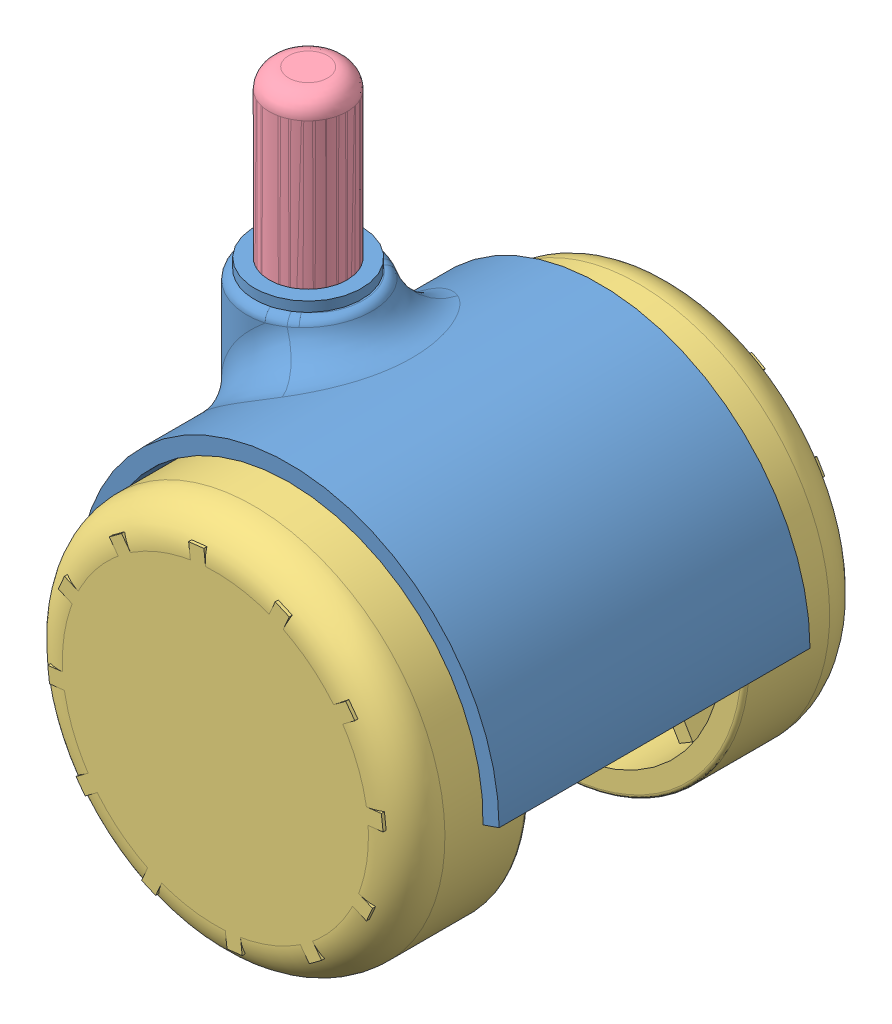
SolidWorks assembly Lam-300120566-ProJ-SubAssembly2, configuration Default. Lengths in mm.
Overall size (68.55 87.61 60.85).
6 component instances, 4 part files, 9 mates.
Components (placement in the parent):
- Lam-300120566-Proj-Part12-1: Lam-300120566-Proj-Part12 [Default] at (21.2947 20.4746 39.6605) size (54.99 40.74 40.64)
- Lam-300120566-Proj-Part15-1: Lam-300120566-Proj-Part15 [Default] at (21.2947 20.4746 50.2805) x (0.988516 0.151117 0) z (0 0 1) size (11.2 11.2 46)
- Lam-300120566-Proj-Part14-2: Lam-300120566-Proj-Part14 [Default] at (-0.1797 7.6742 17.2805) x (-0.512016 0.858976 0) z (0 0 1) size (50 50 19.28)
- Lam-300120566-Proj-Part14-3: Lam-300120566-Proj-Part14 [Default] at (13.2255 44.1365 62.3734) x (-0.946478 -0.322768 0) z (0 0 -1) size (50 50 19.28) (suppressed, hidden)
- Lam-300120566-Proj-Part14-4: Lam-300120566-Proj-Part14 [Default] at (44.232 10.5307 61.5648) x (0.397754 0.917492 0) z (0 0 -1) size (50 50 19.28)
- Lam-300120566-Proj-Part16-1: Lam-300120566-Proj-Part16 [Default] at (3.5147 23.0146 39.6605) size (10.16 50.8 10.16)
Mates (geometry in assembly coordinates):
- Concentric1: concentric aligned: cylinder of Lam-300120566-Proj-Part12-1 through (21.2947 20.4746 19.3405) axis (0 0 1) radius 5.4991; cylinder of Lam-300120566-Proj-Part15-1 through (21.2947 20.4746 53.2805) axis (0 0 1) radius 5.6
- Coincident1: coincident aligned: plane of Lam-300120566-Proj-Part12-1 through (21.2947 20.4746 47.2805) normal (0 0 1); plane of Lam-300120566-Proj-Part15-1 through (20.5391 25.4172 47.2805) normal (0 0 1)
- Concentric3: concentric anti-aligned: cylinder of Lam-300120566-Proj-Part15-1 through (21.2947 20.4746 21.2805) axis (0 0 -1) radius 5; cylinder of Lam-300120566-Proj-Part14-2 through (21.2947 20.4746 14.2805) axis (0 0 1) radius 5
- Coincident3: coincident anti-aligned: plane of Lam-300120566-Proj-Part15-1 through (20.6345 24.7932 14.2805) normal (0 0 -1); plane of Lam-300120566-Proj-Part14-2 through (21.2947 20.4746 14.2805) normal (0 0 1)
- Concentric4: concentric anti-aligned: cylinder of Lam-300120566-Proj-Part15-1 through (21.2947 20.4746 53.2805) axis (0 0 1) radius 5; cylinder of Lam-300120566-Proj-Part14-3 through (21.2947 20.4746 65.3734) axis (0 0 -1) radius 5
- Concentric5: concentric anti-aligned: cylinder of Lam-300120566-Proj-Part15-1 through (21.2947 20.4746 53.2805) axis (0 0 1) radius 5; cylinder of Lam-300120566-Proj-Part14-4 through (21.2947 20.4746 64.5648) axis (0 0 -1) radius 5
- Distance1: distance = 3.2843 mm anti-aligned: plane of Lam-300120566-Proj-Part12-1 through (21.2947 20.4746 47.2805) normal (0 0 1); plane of Lam-300120566-Proj-Part14-4 through (21.2947 20.4746 50.5648) normal (0 0 -1)
- Coincident6: coincident anti-aligned: circle of Lam-300120566-Proj-Part12-1; plane of Lam-300120566-Proj-Part16-1 through (3.5147 23.0146 39.6605) normal (0 -1 0)
- Concentric6: concentric anti-aligned: cylinder of Lam-300120566-Proj-Part12-1 through (3.5147 23.0146 39.6605) axis (0 1 0) radius 5.08; cylinder of Lam-300120566-Proj-Part16-1 through (3.5147 73.8146 39.6605) axis (0 -1 0) radius 5.08
